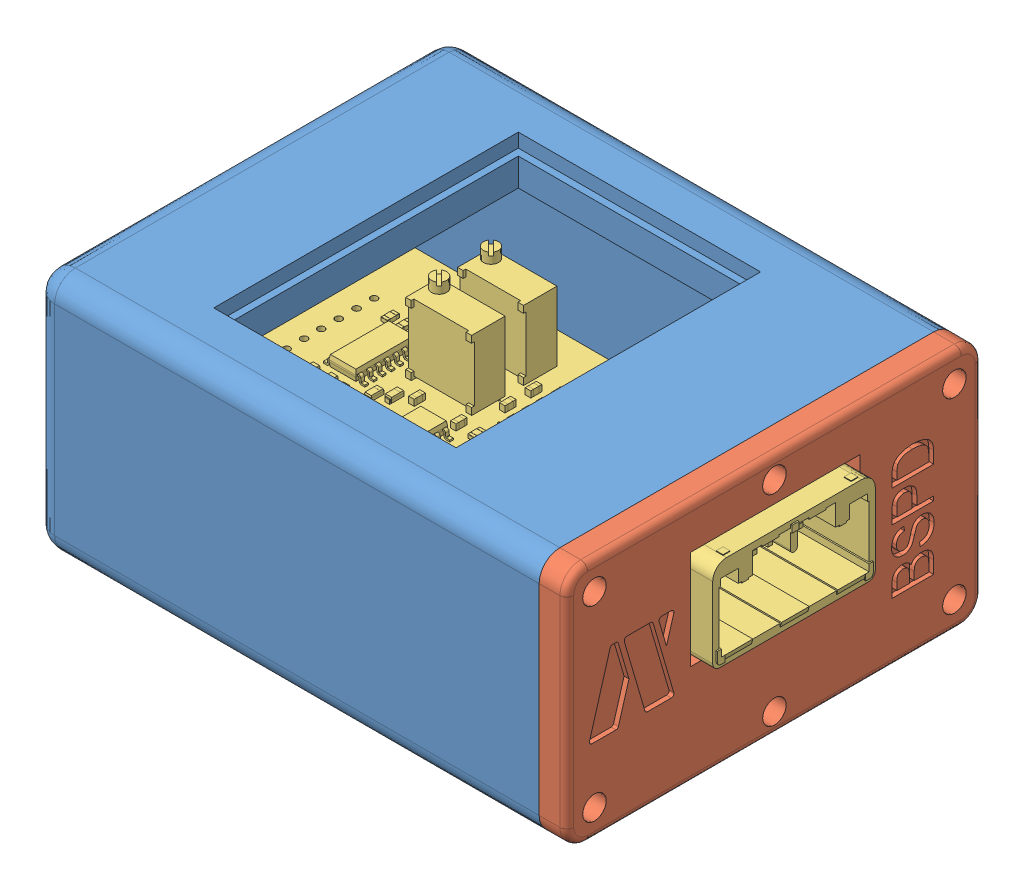
SolidWorks assembly BSPD_RevE_Box_assembly, configuration Default. Lengths in mm.
Overall size (79.94 35 60).
3 component instances, 3 part files, 12 mates.
Components (placement in the parent):
- BSPD_RevE_box-1: BSPD_RevE_box [Default] at (51.7333 56.52 0) size (73 35 60)
- BSPD_RevE_lid^BSPD_RevE_Box_assembly-1: BSPD_RevE_lid^BSPD_RevE_Box_assembly [Default] at (51.7333 56.52 0) x (0 0 -1) z (1 0 0) size (60 35 18) (virtual)
- BSPD_RevE-2: BSPD_RevE [Default] at (16.6333 50.02 -22.5) x (0 0 1) z (-1 0 0) size (45 21.17 78.04)
Mates (geometry in assembly coordinates):
- Parallel1: parallel: plane of BSPD_RevE_box-1 through (-27.3004 45.7475 0) normal (1 0 0); plane of ? through (-28.4004 38.2475 -22.5) normal (-1 0 0)
- Symmetric1: symmetric: plane of BSPD_RevE_box-1 through (-21.2667 56.52 30) normal (0 0 1); plane of BSPD_RevE_box-1 through (-21.2667 56.52 -30) normal (0 0 -1); plane of assembly
- Symmetric2: symmetric: plane of ? through (43.5996 38.2475 -22.5) normal (0 0 -1); plane of ? through (-28.4004 38.2475 22.5) normal (0 0 1)
- Coincident4: coincident: plane of BSPD_RevE_box-1 through (-28.4004 45.7475 0) normal (1 0 0); plane of ? through (-28.4004 38.2475 -22.5) normal (-1 0 0)
- Coincident5: coincident: plane of BSPD_RevE_box-1 through (-28.4004 38.2475 23) normal (0 1 0); plane of ? through (7.5996 38.2475 0) normal (0 -1 0)
- InPlace1: in place: plane of ? through (42.6996 45.7475 0) normal (1 0 0); plane of ? through (42.6996 0 0) normal (1 0 0); moOrthogonalPlaneRef_w of ? through (42.6996 45.7475 0) normal (1 0 0); plane of ? through (42.6996 0 0) normal (0 1 0); plane of ? through (42.6996 45.7475 0) normal (1 0 0); plane of ? through (42.6996 0 0) normal (0 0 -1); plane of BSPD_RevE_box-1 through (51.7333 56.52 0) normal (1 0 0); unknown of BSPD_RevE_lid^BSPD_RevE_Box_assembly-1
- Coincident6: coincident: plane of BSPD_RevE_box-1; plane of BSPD_RevE_lid^BSPD_RevE_Box_assembly-1
- Coincident7: coincident: moOrthogonalPlaneRef_w of BSPD_RevE_box-1 through (51.7333 56.52 0) normal (0 1 0); plane of BSPD_RevE_lid^BSPD_RevE_Box_assembly-1 through (51.7333 56.52 0) normal (0 1 0)
- Coincident8: coincident: moOrthogonalPlaneRef_w of BSPD_RevE_box-1 through (51.7333 56.52 0) normal (0 0 1); plane of BSPD_RevE_lid^BSPD_RevE_Box_assembly-1 through (51.7333 56.52 0) normal (0 0 -1)
- Coincident9: coincident: plane of BSPD_RevE_box-1 through (-19.3667 50.02 23) normal (0 1 0); plane of BSPD_RevE-2 through (16.6333 50.02 0) normal (0 -1 0)
- Coincident10: coincident: plane of BSPD_RevE_box-1 through (-19.3667 56.52 0) normal (1 0 0); plane of BSPD_RevE-2 through (-19.3667 50.02 -22.5) normal (-1 0 0)
- Symmetric3: symmetric: plane of BSPD_RevE-2 through (52.6333 50.02 -22.5) normal (0 0 -1); plane of BSPD_RevE-2 through (-19.3667 50.02 22.5) normal (0 0 1); plane of assembly
